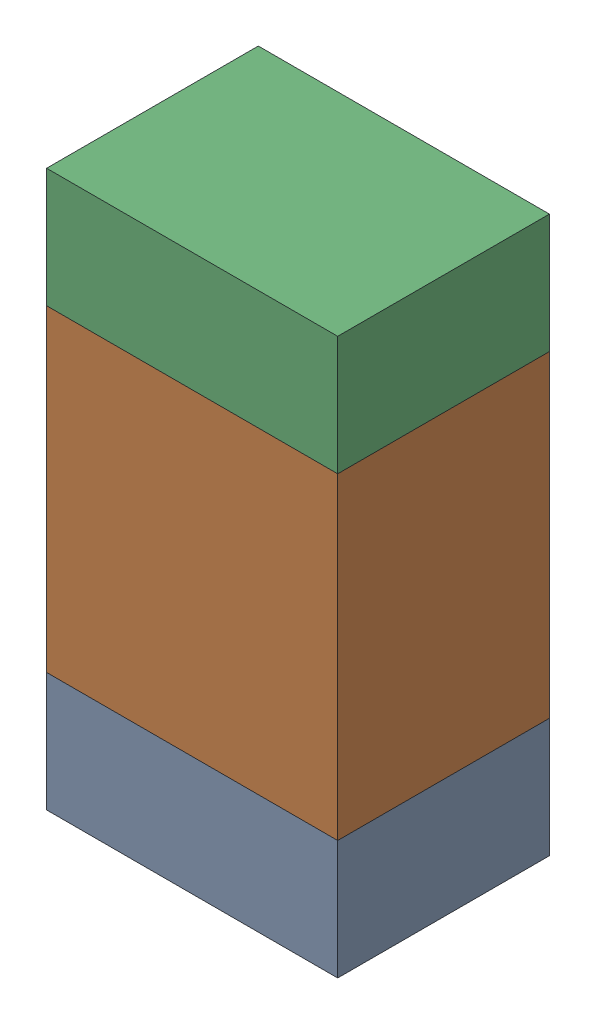
SolidWorks assembly R602_2PCB, configuration Default. Lengths in mm.
Overall size (0.55 1.05 0.4).
6 component instances, 2 part files, 0 mates.
Components (placement in the parent):
- 846483288-1: 846483288 [Default] at (104.8001 102.4876 -2.0638) size (0.55 0.22 0.4)
  - Extruded_12-1: Extruded_12 [Default] at origin size (0.55 0.22 0.4)
- 846483424-1: 846483424 [Default] at (104.8001 102.9001 -2.0638) size (0.55 0.6 0.4)
  - Extruded_13-1: Extruded_13 [Default] at origin size (0.55 0.6 0.4)
- 846483288-2: 846483288 [Default] at (104.8001 103.3126 -2.0638) size (0.55 0.22 0.4)
  - Extruded_12-1: Extruded_12 [Default] at origin size (0.55 0.22 0.4)
